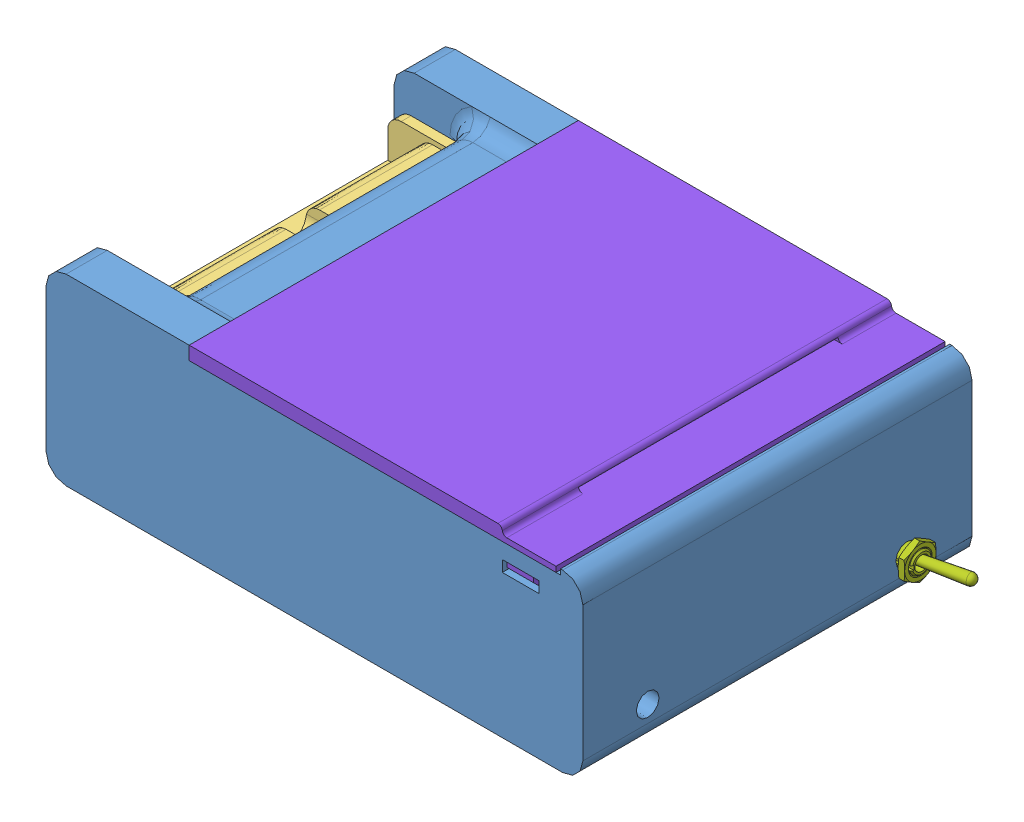
SolidWorks assembly INSTANT_CAM, configuration По умолчанию. Lengths in mm.
Overall size (133.24 41 87).
9 component instances, 8 part files, 17 mates.
Components (placement in the parent):
- B_1-1: B_1 [По умолчанию] at origin size (120 41 87)
- COMMON_18650_BATTERY_HOLDER_DUMMY-1: COMMON_18650_BATTERY_HOLDER_DUMMY [Default] at (37 0 0) size (42 20.5 76.3)
- COMMON_18650_BATTERY_HOLDER_DUMMY-2: COMMON_18650_BATTERY_HOLDER_DUMMY [Default] at (-5 0 0) size (42 20.5 76.3)
- FTP-628MCL701_DUMMY-1: FTP-628MCL701_DUMMY [По умолчанию] at (-39.1 20 -2.5) x (0 0 1) z (1 0 0) size (67.5 18.8 31.5)
- RPI_ZERO_DUMMY_NO_PINS-1: RPI_ZERO_DUMMY_NO_PINS [Default] at (11 -6.6 32.5) x (0 0 -1) z (0 1 0) size (65 30.65 5.45)
- PRINT_HEAD_PCB_DUMMY-1: PRINT_HEAD_PCB_DUMMY [Default] at (31 -6.6 0) x (0 0 1) z (1 0 0) size (47 4.6 37)
- B_2-1: B_2 [По умолчанию] at (0 -13 0) size (106 5.09 83)
- 5_MM_TOGGLE_SWITCH-1: 5_MM_TOGGLE_SWITCH [По умолчанию] at (50.5 -4.8 -29) x (0 1 0) z (1 0 0) size (8.08 8.47 28.12)
- B_3-1: B_3 [Default] at (-28 26.5 0) size (84 8.5 87)
Mates (geometry in assembly coordinates):
- Совпадение1: coincident anti-aligned: plane of B_1-1 through (0 0 0) normal (0 1 0); plane of COMMON_18650_BATTERY_HOLDER_DUMMY-1 through (37 0 0) normal (0 -1 0)
- Совпадение6: coincident anti-aligned: plane of B_1-1 through (0 0 0) normal (0 1 0); plane of COMMON_18650_BATTERY_HOLDER_DUMMY-2 through (-5 0 0) normal (0 -1 0)
- Концентричный4: concentric anti-aligned: cylinder of B_1-1 through (-39 16.75 -2.5) axis (-1 0 0) radius 1.1; cylinder of FTP-628MCL701_DUMMY-1 through (-58.6 16.75 -2.5) axis (1 0 0) radius 1.25
- Концентричный6: concentric aligned: circle of B_1-1; circle of COMMON_18650_BATTERY_HOLDER_DUMMY-1
- Концентричный11: concentric aligned: circle of B_1-1; cylinder of RPI_ZERO_DUMMY_NO_PINS-1 through (7.5 -6.6 -29) axis (0 1 0) radius 1.25
- Совпадение12: coincident anti-aligned: plane of B_1-1 through (-15.5 -5 -29) normal (0 -1 0); plane of RPI_ZERO_DUMMY_NO_PINS-1 through (-4 -5 0) normal (0 1 0)
- Совпадение14: coincident anti-aligned: plane of B_1-1 through (46 -5 -20) normal (0 -1 0); plane of PRINT_HEAD_PCB_DUMMY-1 through (31 -5 0) normal (0 1 0)
- Концентричный13: concentric aligned: cylinder of B_1-1 through (-49.5 0 38) axis (0 -1 0) radius 1.8; cylinder of B_2-1 through (-49.5 -11 38) axis (0 -1 0) radius 1.1
- Концентричный14: concentric aligned: cylinder of B_1-1 through (49.5 0 -38) axis (0 -1 0) radius 1.8; cylinder of B_2-1 through (49.5 -11 -38) axis (0 -1 0) radius 1.1
- Совпадение15: coincident anti-aligned: plane of B_1-1 through (0 -8 0) normal (0 -1 0); plane of B_2-1 through (0 -8 0) normal (0 1 0)
- Концентричный15: concentric anti-aligned: cylinder of B_1-1 through (5.5 -13 0) axis (0 1 0) radius 1.8; cone of COMMON_18650_BATTERY_HOLDER_DUMMY-2 through (5.5 0.9 0) axis (0 -1 0)
- Концентричный16: concentric aligned: cylinder of B_1-1 through (63.5 -4.8 -29) axis (-1 0 0) radius 2.55; cylinder of 5_MM_TOGGLE_SWITCH-1 through (58 -4.8 -29) axis (-1 0 0) radius 2.425
- Параллельность1: parallel anti-aligned: plane of B_1-1 through (0 -2 0) normal (0 -1 0); plane of 5_MM_TOGGLE_SWITCH-1 through (57.5 -2.44 -25.59) normal (0 1 0)
- Совпадение17: coincident anti-aligned: plane of B_1-1 through (57.5 0 0) normal (-1 0 0); plane of 5_MM_TOGGLE_SWITCH-1 through (57.5 -4.8 -29) normal (1 0 0)
- Совпадение18: coincident anti-aligned: plane of B_1-1 through (0 25 -42) normal (0 0 1); plane of B_3-1 through (54 26.5 -42) normal (0 0 -1)
- Совпадение19: coincident anti-aligned: plane of B_1-1 through (0 25 0) normal (0 1 0); plane of B_3-1 through (54 25 0) normal (0 -1 0)
- Совпадение20: coincident anti-aligned: plane of B_1-1 through (-28 25 0) normal (1 0 0); plane of B_3-1 through (-28 26.5 0) normal (-1 0 0)
